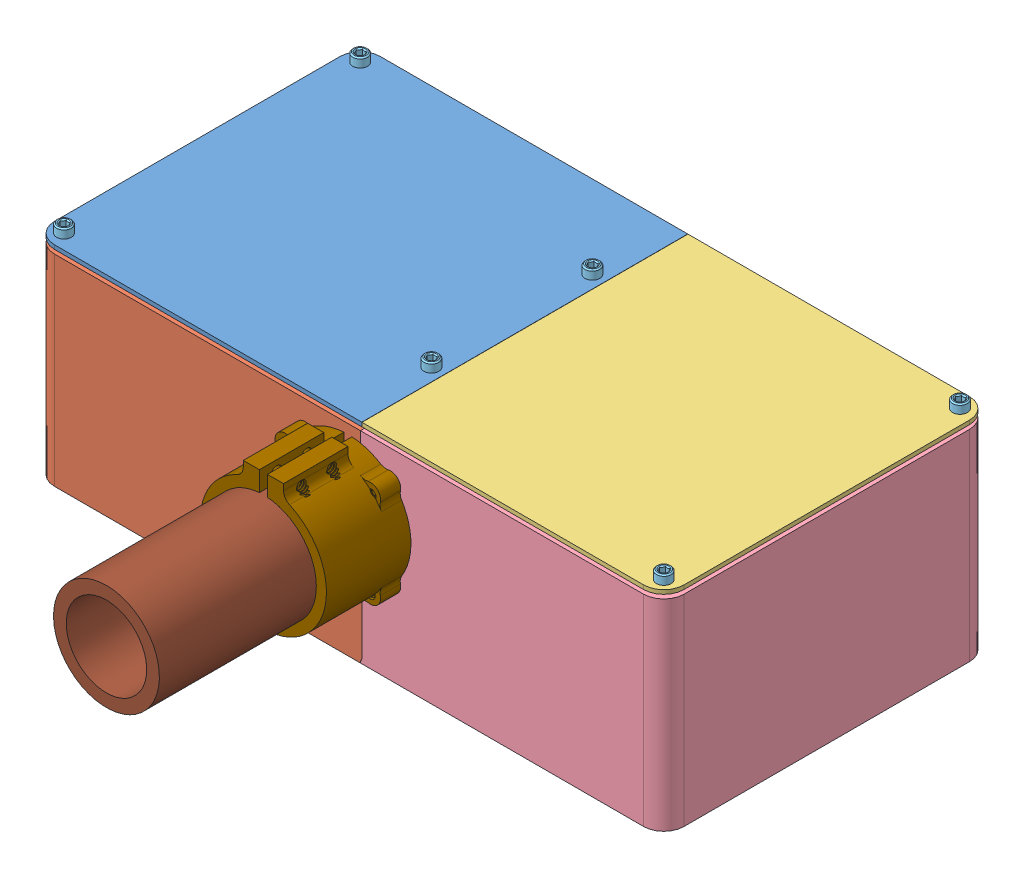
SolidWorks assembly Head Assembly, configuration Default. Lengths in mm.
Overall size (198.69 68.88 181.91).
28 component instances, 11 part files, 54 mates.
Components (placement in the parent):
- Head left back-1: Head left back [Default] at (33.2426 59.719 88.4474) size (103.38 2.54 102.87)
- Head left side-1: Head left side [Left Side] at (83.0901 -3.781 88.4474) size (103.5 63.5 102.87)
- Head right back-1: Head right back [Default] at (132.2391 59.719 88.4474) size (103.5 5.08 102.87)
- Head right side-1: Head right side [Right Side] at (82.3916 -3.781 88.4474) size (103.61 63.5 102.87)
- 4-40_SHCS-1: 4-40_SHCS [4-40 SHCS X .250] at (177.3876 55.909 135.1834) x (1 0 0) z (0 1 0) size (4.65 4.65 9.23)
- 4-40_SHCS-2: 4-40_SHCS [4-40 SHCS X .250] at (82.7091 55.909 113.8474) x (1 0 0) z (0 1 0) size (4.65 4.65 9.23)
- 4-40_SHCS-3: 4-40_SHCS [4-40 SHCS X .250] at (82.7091 55.909 63.0474) x (1 0 0) z (0 1 0) size (4.65 4.65 9.23)
- 4-40_SHCS-4: 4-40_SHCS [4-40 SHCS X .250] at (177.3876 55.909 41.7114) x (1 0 0) z (0 1 0) size (4.65 4.65 9.23)
- 4-40_SHCS-5: 4-40_SHCS [4-40 SHCS X .250] at (-11.9059 55.909 135.1834) x (0.995254 0 0.097312) z (0 1 0) size (4.65 4.65 9.23)
- 4-40_SHCS-6: 4-40_SHCS [4-40 SHCS X .250] at (-11.9059 55.909 41.7114) x (-0.428601 0 -0.903494) z (0 1 0) size (4.65 4.65 9.23)
- 4-40_SHCS-7: 4-40_SHCS [4-40 SHCS X .250] at (82.3916 38.129 43.3624) x (-0.923728 -0.383049 0) z (0 0 -1) size (4.65 4.65 9.23)
- 4-40_SHCS-8: 4-40_SHCS [4-40 SHCS X .250] at (82.3916 17.809 43.3624) x (-0.923728 -0.383049 0) z (0 0 -1) size (4.65 4.65 9.23)
- logic shifter board-1: logic shifter board [Default] at (133.1916 27.969 88.2569) x (0 0 -1) z (1 0 0) size (64.77 1.27 39.37)
- hex_nut-1: hex_nut [#4-40] at (150.3366 25.429 58.4119) x (-0.837169 0 -0.546944) z (-0.546944 0 0.837169) size (6.35 2.49 8.06)
- hex_nut-2: hex_nut [#4-40] at (116.0466 25.429 58.4119) x (-0.837169 0 -0.546944) z (-0.546944 0 0.837169) size (6.35 2.49 8.06)
- hex_nut-3: hex_nut [#4-40] at (116.0466 25.429 118.4829) x (-0.837169 0 -0.546944) z (-0.546944 0 0.837169) size (6.35 2.49 8.06)
- hex_nut-4: hex_nut [#4-40] at (150.3366 25.429 118.4829) x (-0.837169 0 -0.546944) z (-0.546944 0 0.837169) size (6.35 2.49 8.06)
- 4-40_SHCS-9: 4-40_SHCS [4-40 SHCS X .250] at (150.3366 22.889 58.4119) x (1 0 0) z (0 1 0) size (4.65 4.65 9.23)
- 4-40_SHCS-10: 4-40_SHCS [4-40 SHCS X .250] at (116.0466 22.889 58.4119) x (1 0 0) z (0 1 0) size (4.65 4.65 9.23)
- 4-40_SHCS-11: 4-40_SHCS [4-40 SHCS X .250] at (150.3366 22.889 118.4829) x (1 0 0) z (0 1 0) size (4.65 4.65 9.23)
- 4-40_SHCS-12: 4-40_SHCS [4-40 SHCS X .250] at (116.0466 22.889 118.4829) x (1 0 0) z (0 1 0) size (4.65 4.65 9.23)
- LED Matrix-1: LED Matrix [Default] at (-11.5884 12.729 40.1874) x (1 0 0) z (0 -1 0) size (190.5 96.52 13.21)
- PVC Clamping Hub-1: PVC Clamping Hub [Default] at (82.3916 36.859 166.5524) x (1 0 0) z (0 1 0) size (39.77 26.79 42.81)
- 6-32_SHCS-5: 6-32_SHCS [6-32 SHCS X .250] at (95.862 50.3293 143.0574) x (-0.883865 -0.467742 0) z (0 0 -1) size (5.74 5.74 9.86)
- 6-32_SHCS-6: 6-32_SHCS [6-32 SHCS X .250] at (96.5605 24.0871 143.0574) x (-0.467742 0.883865 0) z (0 0 -1) size (5.74 5.74 9.86)
- 6-32_SHCS-7: 6-32_SHCS [6-32 SHCS X .250] at (70.3182 23.3886 143.0574) x (0.883865 0.467742 0) z (0 0 -1) size (5.74 5.74 9.86)
- 6-32_SHCS-8: 6-32_SHCS [6-32 SHCS X .250] at (69.6197 49.6308 143.0574) x (0.467742 -0.883865 0) z (0 0 -1) size (5.74 5.74 9.86)
- 3in PVC Pipe-1: 3in PVC Pipe [Default] at (82.3916 36.859 139.8824) x (0 0 1) z (-0.871872 0.489734 0) size (76.2 33.4 33.4)
Mates (geometry in assembly coordinates):
- Coincident1: coincident aligned: plane of Head left back-1 through (33.2426 62.259 88.4474) normal (0 1 0); plane of Head right back-1 through (132.2391 62.259 88.4474) normal (0 1 0)
- Concentric1: concentric anti-aligned: cylinder of Head right back-1 through (82.7091 60.989 113.8474) axis (0 1 0) radius 1.1303; cylinder of 4-40_SHCS-2 through (82.7091 74.959 113.8474) axis (0 -1 0) radius 2.3241
- Concentric2: concentric aligned: cylinder of Head right back-1 through (82.7091 60.989 63.0474) axis (0 1 0) radius 1.1303; cylinder of Head left back-1 through (82.7091 62.259 63.0474) axis (0 1 0) radius 1.778
- Concentric3: concentric anti-aligned: cylinder of Head right back-1 through (82.7091 60.989 63.0474) axis (0 1 0) radius 1.1303; cylinder of 4-40_SHCS-3 through (82.7091 74.959 63.0474) axis (0 -1 0) radius 2.3241
- Concentric4: concentric anti-aligned: cylinder of Head left back-1 through (82.7091 62.259 113.8474) axis (0 1 0) radius 1.778; cylinder of 4-40_SHCS-2 through (82.7091 74.959 113.8474) axis (0 -1 0) radius 2.3241
- Concentric5: concentric aligned: cylinder of Head right side-1 through (177.3876 59.719 135.1834) axis (0 1 0) radius 1.1303; cylinder of Head right back-1 through (177.3876 62.259 135.1834) axis (0 1 0) radius 1.7272
- Concentric6: concentric anti-aligned: cylinder of Head right side-1 through (177.3876 59.719 135.1834) axis (0 1 0) radius 1.1303; cylinder of 4-40_SHCS-1 through (177.3876 74.959 135.1834) axis (0 -1 0) radius 2.3241
- Concentric7: concentric aligned: cylinder of Head right side-1 through (177.3876 59.719 41.7114) axis (0 1 0) radius 1.1303; cylinder of Head right back-1 through (177.3876 62.259 41.7114) axis (0 1 0) radius 1.7272
- Concentric8: concentric anti-aligned: cylinder of Head right side-1 through (177.3876 59.719 41.7114) axis (0 1 0) radius 1.1303; cylinder of 4-40_SHCS-4 through (177.3876 74.959 41.7114) axis (0 -1 0) radius 2.3241
- Concentric9: concentric anti-aligned: cylinder of 4-40_SHCS-5 through (-11.9059 74.959 135.1834) axis (0 -1 0) radius 2.3241; cylinder of Head left side-1 through (-11.9059 59.719 135.1834) axis (0 1 0) radius 1.1303
- Concentric10: concentric anti-aligned: cylinder of 4-40_SHCS-5 through (-11.9059 74.959 135.1834) axis (0 -1 0) radius 2.3241; cylinder of Head left back-1 through (-11.9059 62.259 135.1834) axis (0 1 0) radius 1.632
- Concentric11: concentric aligned: cylinder of Head left back-1 through (-11.9059 62.259 41.7114) axis (0 1 0) radius 1.632; cylinder of Head left side-1 through (-11.9059 59.719 41.7114) axis (0 1 0) radius 1.1303
- Concentric12: concentric anti-aligned: cylinder of Head left back-1 through (-11.9059 62.259 41.7114) axis (0 1 0) radius 1.632; cylinder of 4-40_SHCS-6 through (-11.9059 74.959 41.7114) axis (0 -1 0) radius 2.3241
- Coincident2: coincident anti-aligned: plane of Head right back-1 through (132.2391 62.259 88.4474) normal (0 1 0); plane of 4-40_SHCS-1 through (177.3876 62.259 135.1834) normal (0 -1 0)
- Coincident3: coincident anti-aligned: plane of Head right back-1 through (132.2391 62.259 88.4474) normal (0 1 0); plane of 4-40_SHCS-4 through (177.3876 62.259 41.7114) normal (0 -1 0)
- Coincident4: coincident anti-aligned: plane of Head right back-1 through (132.2391 62.259 88.4474) normal (0 1 0); plane of 4-40_SHCS-6 through (-11.9059 62.259 41.7114) normal (0 -1 0)
- Coincident5: coincident anti-aligned: plane of Head right back-1 through (132.2391 62.259 88.4474) normal (0 1 0); plane of 4-40_SHCS-5 through (-11.9059 62.259 135.1834) normal (0 -1 0)
- Coincident6: coincident anti-aligned: plane of Head left back-1 through (33.2426 62.259 88.4474) normal (0 1 0); plane of 4-40_SHCS-2 through (82.7091 62.259 113.8474) normal (0 -1 0)
- Coincident7: coincident anti-aligned: plane of Head left back-1 through (33.2426 62.259 88.4474) normal (0 1 0); plane of 4-40_SHCS-3 through (82.7091 62.259 63.0474) normal (0 -1 0)
- Coincident8: coincident anti-aligned: plane of Head left back-1 through (33.2426 59.719 88.4474) normal (0 -1 0); plane of Head left side-1 through (83.0901 59.719 88.4474) normal (0 1 0)
- Coincident9: coincident anti-aligned: plane of Head left back-1 through (33.2426 59.719 88.4474) normal (0 -1 0); plane of Head right side-1 through (82.3916 59.719 88.4474) normal (0 1 0)
- Concentric13: concentric anti-aligned: cylinder of Head right side-1 through (82.3916 38.129 38.5237) axis (0 0 -1) radius 1.0795; cylinder of 4-40_SHCS-7 through (82.3916 38.129 24.3124) axis (0 0 1) radius 2.3241
- Concentric14: concentric anti-aligned: cylinder of Head right side-1 through (82.3916 17.809 38.5237) axis (0 0 -1) radius 1.0795; cylinder of 4-40_SHCS-8 through (82.3916 17.809 24.3124) axis (0 0 1) radius 2.3241
- Coincident10: coincident anti-aligned: plane of Head right side-1 through (182.0866 0.029 37.0124) normal (0 0 -1); plane of 4-40_SHCS-8 through (82.3916 17.809 37.0124) normal (0 0 1)
- Coincident11: coincident anti-aligned: plane of Head right side-1 through (182.0866 0.029 37.0124) normal (0 0 -1); plane of 4-40_SHCS-7 through (82.3916 38.129 37.0124) normal (0 0 1)
- Concentric15: concentric aligned: cylinder of Head right side-1 through (116.0466 27.969 58.4119) axis (0 1 0) radius 1.632; cylinder of logic shifter board-1 through (116.0466 29.239 58.4119) axis (0 1 0) radius 1.632
- Coincident12: coincident anti-aligned: plane of Head right side-1 through (82.3916 27.969 88.4474) normal (0 1 0); plane of logic shifter board-1 through (133.1916 27.969 88.2569) normal (0 -1 0)
- Concentric17: concentric aligned: cylinder of Head right side-1 through (150.3366 27.969 58.4119) axis (0 1 0) radius 1.632; cylinder of logic shifter board-1 through (150.3366 29.239 58.4119) axis (0 1 0) radius 1.632
- Concentric18: concentric anti-aligned: cylinder of Head right side-1 through (150.3366 27.969 58.4119) axis (0 1 0) radius 1.632; cylinder of 4-40_SHCS-9 through (150.3366 41.939 58.4119) axis (0 -1 0) radius 2.3241
- Concentric19: concentric anti-aligned: cylinder of Head right side-1 through (150.3366 27.969 58.4119) axis (0 1 0) radius 1.632; cylinder of hex_nut-1 through (150.3366 25.0354 58.4119) axis (0 -1 0) radius 1.0787
- Concentric20: concentric anti-aligned: cylinder of Head right side-1 through (116.0466 27.969 58.4119) axis (0 1 0) radius 1.632; cylinder of 4-40_SHCS-10 through (116.0466 41.939 58.4119) axis (0 -1 0) radius 2.3241
- Concentric21: concentric anti-aligned: cylinder of Head right side-1 through (116.0466 27.969 58.4119) axis (0 1 0) radius 1.632; cylinder of hex_nut-2 through (116.0466 25.0354 58.4119) axis (0 -1 0) radius 1.0787
- Concentric22: concentric anti-aligned: cylinder of Head right side-1 through (150.3366 27.969 118.4829) axis (0 1 0) radius 1.632; cylinder of 4-40_SHCS-11 through (150.3366 41.939 118.4829) axis (0 -1 0) radius 2.3241
- Concentric23: concentric anti-aligned: cylinder of Head right side-1 through (150.3366 27.969 118.4829) axis (0 1 0) radius 1.632; cylinder of hex_nut-4 through (150.3366 25.0354 118.4829) axis (0 -1 0) radius 1.0787
- Concentric24: concentric anti-aligned: cylinder of Head right side-1 through (116.0466 27.969 118.4829) axis (0 1 0) radius 1.632; cylinder of 4-40_SHCS-12 through (116.0466 41.939 118.4829) axis (0 -1 0) radius 2.3241
- Concentric25: concentric anti-aligned: cylinder of Head right side-1 through (116.0466 27.969 118.4829) axis (0 1 0) radius 1.632; cylinder of hex_nut-3 through (116.0466 24.4004 118.4829) axis (0 -1 0) radius 1.0787
- Coincident13: coincident anti-aligned: plane of logic shifter board-1 through (133.1916 29.239 88.2569) normal (0 1 0); plane of 4-40_SHCS-12 through (116.0466 29.239 118.4829) normal (0 -1 0)
- Coincident14: coincident anti-aligned: plane of logic shifter board-1 through (133.1916 29.239 88.2569) normal (0 1 0); plane of 4-40_SHCS-11 through (150.3366 29.239 118.4829) normal (0 -1 0)
- Coincident15: coincident anti-aligned: plane of logic shifter board-1 through (133.1916 29.239 88.2569) normal (0 1 0); plane of 4-40_SHCS-9 through (150.3366 29.239 58.4119) normal (0 -1 0)
- Coincident16: coincident anti-aligned: plane of logic shifter board-1 through (133.1916 29.239 88.2569) normal (0 1 0); plane of 4-40_SHCS-10 through (116.0466 29.239 58.4119) normal (0 -1 0)
- Coincident17: coincident anti-aligned: plane of Head right side-1 through (82.3916 25.429 88.4474) normal (0 -1 0); plane of hex_nut-1 through (152.3418 25.429 55.3427) normal (0 1 0)
- Coincident18: coincident anti-aligned: plane of Head right side-1 through (82.3916 25.429 88.4474) normal (0 -1 0); circle of hex_nut-2
- Coincident19: coincident anti-aligned: plane of Head right side-1 through (82.3916 25.429 88.4474) normal (0 -1 0); plane of hex_nut-4 through (152.3418 25.429 115.4137) normal (0 1 0)
- Coincident20: coincident anti-aligned: plane of Head right side-1 through (82.3916 25.429 88.4474) normal (0 -1 0); plane of hex_nut-3 through (118.0518 25.429 115.4137) normal (0 1 0)
- Coincident21: coincident anti-aligned: plane of Head right side-1 through (178.9116 202.9716 40.1874) normal (0 0 1); plane of LED Matrix-1 through (-11.5884 0.029 40.1874) normal (0 0 -1)
- Coincident22: coincident anti-aligned: plane of Head right side-1 through (178.9116 202.9716 136.7074) normal (-1 0 0); plane of LED Matrix-1 through (178.9116 0.029 40.1874) normal (1 0 0)
- Coincident24: coincident anti-aligned: plane of Head right side-1 through (82.3916 0.029 88.4474) normal (0 1 0); plane of LED Matrix-1 through (-11.5884 0.029 40.1874) normal (0 -1 0)
- Concentric26: concentric anti-aligned: cylinder of Head right side-1 through (82.3916 36.859 141.7874) axis (0 0 -1) radius 9.525; cylinder of PVC Clamping Hub-1 through (82.3916 36.859 139.8824) axis (0 0 1) radius 16.7005
- Concentric29: concentric aligned: cylinder of Head right side-1 through (95.862 50.3293 136.7074) axis (0 0 -1) radius 1.8986; cylinder of PVC Clamping Hub-1 through (95.862 50.3293 139.8824) axis (0 0 -1) radius 1.3526
- Concentric30: concentric anti-aligned: cylinder of Head right side-1 through (95.862 50.3293 136.7074) axis (0 0 -1) radius 1.8986; cylinder of 6-32_SHCS-5 through (95.862 50.3293 124.0074) axis (0 0 1) radius 2.8702
- Coincident25: coincident anti-aligned: plane of Head left side-1 through (-16.6049 0.029 139.8824) normal (0 0 1); plane of PVC Clamping Hub-1 through (82.3916 36.859 139.8824) normal (0 0 -1)
- Coincident26: coincident anti-aligned: plane of Head right side-1 through (82.3916 202.9716 136.7074) normal (0 0 -1); plane of 6-32_SHCS-5 through (95.862 50.3293 136.7074) normal (0 0 1)
- Concentric31: concentric anti-aligned: cylinder of PVC Clamping Hub-1 through (82.3916 36.859 139.8824) axis (0 0 1) radius 16.7005; cylinder of 3in PVC Pipe-1 through (82.3916 36.859 216.0824) axis (0 0 -1) radius 16.7005
- Coincident27: coincident anti-aligned: plane of Head left side-1 through (-16.6049 0.029 139.8824) normal (0 0 1); plane of 3in PVC Pipe-1 through (82.3916 36.859 139.8824) normal (0 0 -1)
